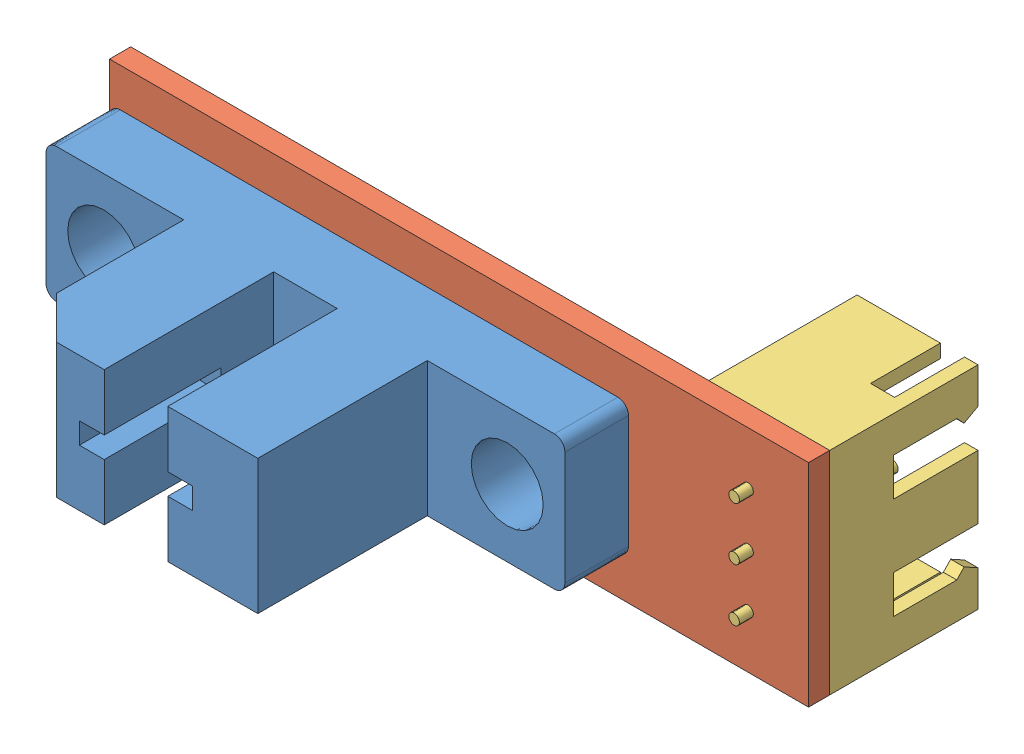
SolidWorks assembly Endstop_Opto_TCST2103, configuration Défaut. Lengths in mm.
Overall size (33 10 19).
3 component instances, 3 part files, 12 mates.
Components (placement in the parent):
- TCST2103^Endstop_Opto_TCST2103-1: TCST2103^Endstop_Opto_TCST2103 [Défaut] x (1 0 0) z (0 1 0) size (24.5 11 6.35) (virtual)
- PCB^Endstop_Opto_TCST2103-1: PCB^Endstop_Opto_TCST2103 [Défaut] x (1 0 0) z (0 0 -1) size (33 10 1) (virtual)
- Connector^Endstop_Opto_TCST2103-1: Connector^Endstop_Opto_TCST2103 [Défaut] at (0 0 -1) x (1 0 0) z (0 0 -1) size (5.71 10 8.66) (virtual)
Mates (geometry in assembly coordinates):
- Sur place1: in place: plane of TCST2103^Endstop_Opto_TCST2103-1 through (0 0 0) normal (0 1 0); moOrthogonalPlaneRef_w of TCST2103^Endstop_Opto_TCST2103-1 through (0 0 0) normal (0 0 -1); line of TCST2103^Endstop_Opto_TCST2103-1 through (55 -55 0) axis (0 0 1); unknown of TCST2103^Endstop_Opto_TCST2103-1
- Coïncidente1: coincident aligned: plane of TCST2103^Endstop_Opto_TCST2103-1; plane of assembly
- Coïncidente2: coincident aligned: plane of TCST2103^Endstop_Opto_TCST2103-1 through (0 0 0) normal (0 0 -1); moOrthogonalPlaneRef_w of assembly
- Coïncidente3: coincident anti-aligned: plane of TCST2103^Endstop_Opto_TCST2103-1; moOrthogonalPlaneRef_w of assembly
- Sur place2: in place: plane of TCST2103^Endstop_Opto_TCST2103-1 through (-12.25 3.175 0) normal (0 0 -1); plane of ? through (0 0 0) normal (0 0 -1); plane of TCST2103^Endstop_Opto_TCST2103-1 through (-12.25 3.175 0) normal (0 0 -1); line of ? through (-55 0 0) axis (0 0 1); plane of TCST2103^Endstop_Opto_TCST2103-1 through (-12.25 3.175 0) normal (0 0 -1); plane of ? through (0 0 0) normal (-1 0 0); plane of TCST2103^Endstop_Opto_TCST2103-1 through (-12.25 3.175 0) normal (0 0 -1); unknown of PCB^Endstop_Opto_TCST2103-1
- Coïncidente4: coincident aligned: plane of TCST2103^Endstop_Opto_TCST2103-1; plane of PCB^Endstop_Opto_TCST2103-1
- Coïncidente5: coincident aligned: moOrthogonalPlaneRef_w of TCST2103^Endstop_Opto_TCST2103-1 through (0 0 0) normal (0 -1 0); plane of PCB^Endstop_Opto_TCST2103-1 through (0 0 0) normal (0 -1 0)
- Coïncidente6: coincident anti-aligned: moOrthogonalPlaneRef_w of TCST2103^Endstop_Opto_TCST2103-1 through (0 0 0) normal (-1 0 0); plane of PCB^Endstop_Opto_TCST2103-1
- Sur place3: in place: plane of PCB^Endstop_Opto_TCST2103-1 through (0 0 -1) normal (0 0 -1); plane of ? through (0 0 -1) normal (0 0 -1); plane of PCB^Endstop_Opto_TCST2103-1 through (0 0 -1) normal (0 0 -1); unknown of ?; plane of PCB^Endstop_Opto_TCST2103-1 through (0 0 -1) normal (0 0 -1); plane of ? through (0 0 -1) normal (-1 0 0); plane of PCB^Endstop_Opto_TCST2103-1 through (0 0 -1) normal (0 0 -1); unknown of Connector^Endstop_Opto_TCST2103-1
- Coïncidente7: coincident aligned: plane of PCB^Endstop_Opto_TCST2103-1; plane of Connector^Endstop_Opto_TCST2103-1
- Coïncidente8: coincident aligned: moOrthogonalPlaneRef_w of PCB^Endstop_Opto_TCST2103-1 through (0 0 -1) normal (0 -1 0); plane of Connector^Endstop_Opto_TCST2103-1 through (0 0 -1) normal (0 -1 0)
- Coïncidente9: coincident anti-aligned: moOrthogonalPlaneRef_w of PCB^Endstop_Opto_TCST2103-1 through (0 0 -1) normal (-1 0 0); plane of Connector^Endstop_Opto_TCST2103-1
